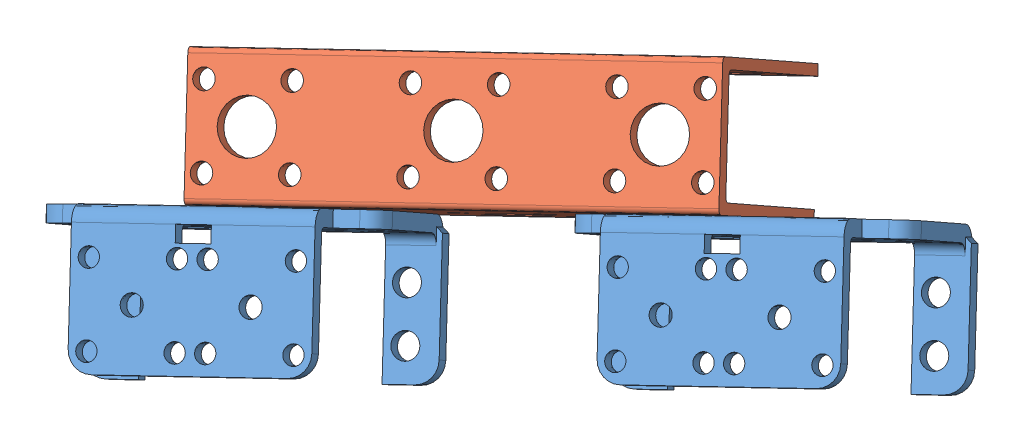
SolidWorks assembly abdomen_support, configuration Predeterminado. Lengths in mm.
Overall size (151.57 87.66 109.24).
3 component instances, 2 part files, 6 mates.
Components (placement in the parent):
- multi_purpose_bracket-1: multi_purpose_bracket [Predeterminado] at (-430.1174 -360.3056 -214.1479) x (0.871511 0.187309 -0.453192) z (-0.283273 -0.562078 -0.777061) size (60 27 38.5)
- multi_purpose_bracket-2: multi_purpose_bracket [Predeterminado] at (-352.5529 -343.635 -254.482) x (0.871511 0.187309 -0.453192) z (-0.283273 -0.562078 -0.777061) size (60 27 38.5)
- channel_bracket-1: channel_bracket [Predeterminado] at (-391.2794 -331.8617 -225.8966) x (0.871511 0.187309 -0.453192) z (-0.40028 0.805595 -0.436798) size (90 43 25)
Mates (geometry in assembly coordinates):
- Concéntrica8: concentric aligned: cylinder of multi_purpose_bracket-1 through (-425.0822 -365.3471 -228.0626) axis (0.40028 -0.805595 0.436798) radius 5.3; cylinder of channel_bracket-1 through (-435.0888 -345.208 -238.9821) axis (0.40028 -0.805595 0.436798) radius 5.4
- Concéntrica9: concentric aligned: cylinder of multi_purpose_bracket-2 through (-364.5122 -352.3291 -259.5595) axis (0.40028 -0.805595 0.436798) radius 5.3; circle of channel_bracket-1
- Coincidente21: coincident anti-aligned: plane of multi_purpose_bracket-2 through (-352.5529 -343.635 -254.482) normal (-0.40028 0.805595 -0.436798); plane of channel_bracket-1 through (-426.3438 -352.0468 -202.3741) normal (0.40028 -0.805595 0.436798)
- Coincidente22: coincident anti-aligned: plane of multi_purpose_bracket-1 through (-430.1174 -360.3056 -214.1479) normal (-0.40028 0.805595 -0.436798); plane of channel_bracket-1 through (-426.3438 -352.0468 -202.3741) normal (0.40028 -0.805595 0.436798)
- Concéntrica10: concentric anti-aligned: cylinder of multi_purpose_bracket-2 through (-358.1429 -359.1404 -266.5092) axis (-0.40028 0.805595 -0.436798) radius 1.8; cylinder of channel_bracket-1 through (-370.1513 -334.9725 -279.6132) axis (0.40028 -0.805595 0.436798) radius 1.9
- Concéntrica11: concentric anti-aligned: cylinder of multi_purpose_bracket-1 through (-431.6542 -374.9398 -228.2828) axis (-0.40028 0.805595 -0.436798) radius 1.9; cylinder of channel_bracket-1 through (-443.6627 -350.7719 -241.3867) axis (0.40028 -0.805595 0.436798) radius 1.9
